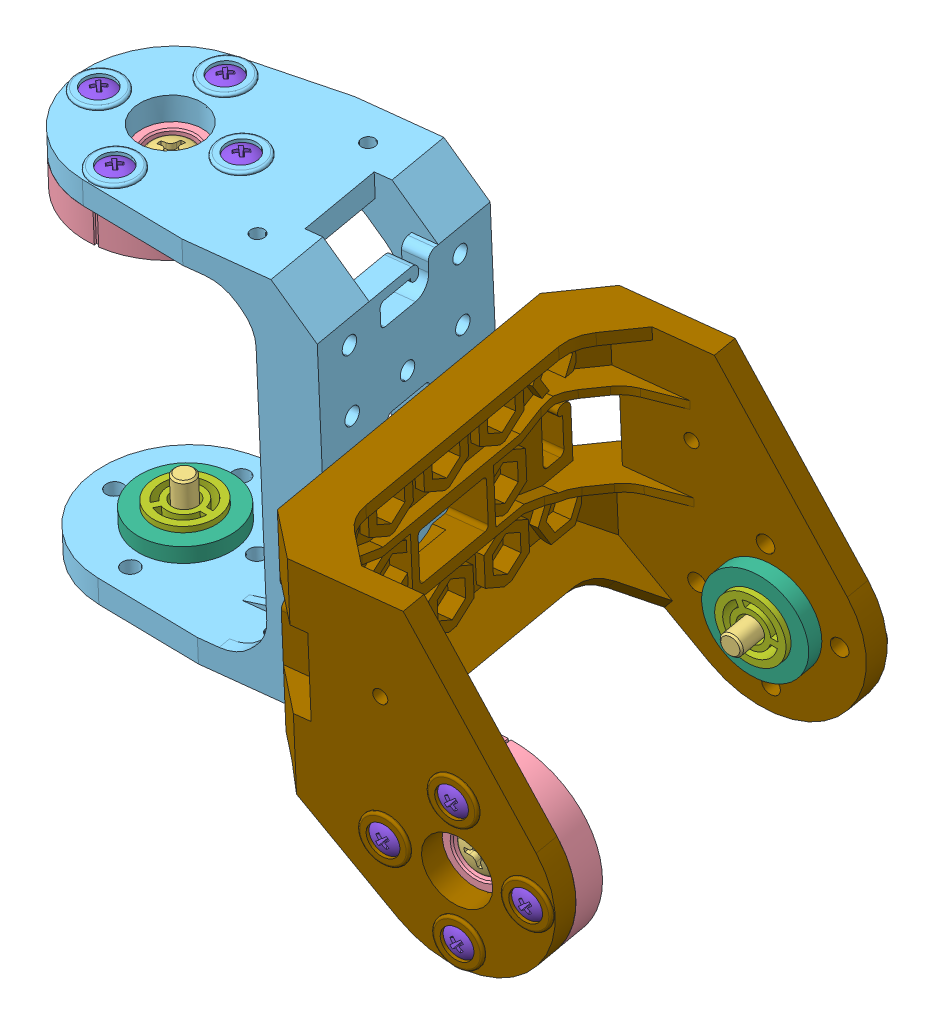
SolidWorks assembly bras, configuration Défaut. Lengths in mm.
Overall size (80.13 65.03 56.04).
31 component instances, 9 part files, 38 mates.
Components (placement in the parent):
- ASSY_GEAR-WHEEL___DUMMY-1: ASSY_GEAR-WHEEL___DUMMY [Défaut] at (-92.8438 48.768 19.6267) x (0.999774 -0.01458 -0.015465) z (0.015465 0.998153 0.058742) size (6.5 6.5 5.51)
- BHS_M2_6X8-1: BHS_M2_6X8 [Défaut] at (-92.8427 48.8379 19.6308) x (0.999774 -0.01458 -0.015465) z (0.015465 0.998153 0.058742) size (5.92 5.92 9.6)
  - BHS_M2_6X8-1: BHS_M2_6X8 [Défaut] at origin size (2.15 2.15 8)
  - BHS_M2_6X8-1-1: BHS_M2_6X8-1 [Défaut] at origin size (5.92 5.92 9.6)
- DC04_B01_HORN2_DUMMY-1: DC04_B01_HORN2_DUMMY [Défaut] at (-92.8427 48.8379 19.6308) x (-0.992163 0.008034 0.124691) z (0.015465 0.998153 0.058742) size (22 22 6.71)
- F2-1: F2 [Défaut] at (-92.8447 48.7081 19.6232) x (0.015465 0.998153 0.058742) z (0.992163 -0.008034 -0.124691) size (48.8 25 37)
- WA-1: WA [Défaut] at (-93.1695 27.7469 18.3896) x (0.999774 -0.01458 -0.015465) z (0.01458 -0.058968 0.998153) size (12 1.9 12)
- BU-1: BU [Défaut] at (-93.1293 30.3421 18.5423) x (0.999774 -0.01458 -0.015465) z (-0.01458 0.058968 -0.998153) size (10 7.1 10)
- BU-2: BU [Défaut] at (-46.8581 26.9638 -6.0328) x (0.982813 -0.130125 -0.130942) z (0.136768 0.989668 0.043041) size (10 7.1 10)
- WA-4: WA [Défaut] at (-47.1805 27.1204 -8.6079) x (0.982813 -0.130125 -0.130942) z (-0.136768 -0.989668 -0.043041) size (12 1.9 12)
- BHS_M2_6X8-2: BHS_M2_6X8 [Défaut] at (-45.0751 26.098 8.21) x (0.519447 -0.846526 -0.116487) z (-0.123989 0.06021 -0.990455) size (5.92 5.92 9.6)
  - BHS_M2_6X8-1: BHS_M2_6X8 [Défaut] at origin size (2.15 2.15 8)
  - BHS_M2_6X8-1-1: BHS_M2_6X8-1 [Défaut] at origin size (5.92 5.92 9.6)
- BHS_M2_6X8-3: BHS_M2_6X8 [Défaut] at (-92.9069 44.6955 19.387) x (-0.917934 -0.00912 0.396627) z (-0.015465 -0.998153 -0.058742) size (5.92 5.92 9.6)
  - BHS_M2_6X8-1: BHS_M2_6X8 [Défaut] at origin size (2.15 2.15 8)
  - BHS_M2_6X8-1-1: BHS_M2_6X8-1 [Défaut] at origin size (5.92 5.92 9.6)
- vis M2-12: vis M2 [B18.6.7M - M2 x 0.4 x 2.5 Type I Cross Recessed PHMS --2.5N] at (-93.4562 73.7443 13.1446) x (-0.015465 -0.998153 -0.058742) z (0.664013 0.033671 -0.746963) size (4.08 4 4)
- vis M2-13: vis M2 [B18.6.7M - M2 x 0.4 x 2.5 Type I Cross Recessed PHMS --2.5N] at (-100.4016 73.3269 22.0658) x (-0.015465 -0.998153 -0.058742) z (0.664013 0.033671 -0.746963) size (4.08 4 4)
- vis M2-14: vis M2 [B18.6.7M - M2 x 0.4 x 2.5 Type I Cross Recessed PHMS --2.5N] at (-84.527 73.1984 20.0707) x (-0.015465 -0.998153 -0.058742) z (0.664013 0.033671 -0.746963) size (4.08 4 4)
- vis M2-15: vis M2 [B18.6.7M - M2 x 0.4 x 2.5 Type I Cross Recessed PHMS --2.5N] at (-91.4724 72.781 28.9919) x (-0.015465 -0.998153 -0.058742) z (0.664013 0.033671 -0.746963) size (4.08 4 4)
- axe roue avec F1-1: axe roue avec F1 [Défaut] at (-44.2439 25.4602 13.5431) x (-0.984524 -0.132048 0.115219) z (0.123989 -0.06021 0.990455) size (38.99 42.39 48.8)
  - ASSY_GEAR-WHEEL___DUMMY-1: ASSY_GEAR-WHEEL___DUMMY [Défaut] at (0.1197 -0.3305 -1.3436) size (6.5 6.5 5.51)
  - BHS_M2_6X8-1: BHS_M2_6X8 [Défaut] at (0.1197 -0.3305 -1.2736) size (5.92 5.92 9.6)
    - BHS_M2_6X8-1: BHS_M2_6X8 [Défaut] at origin size (2.15 2.15 8)
    - BHS_M2_6X8-1-1: BHS_M2_6X8-1 [Défaut] at origin size (5.92 5.92 9.6)
  - DC04_B01_HORN2_DUMMY-1: DC04_B01_HORN2_DUMMY [Défaut] at (0.1197 -0.3305 -1.2736) x (0.990114 -0.140262 0) z (0 0 1) size (22 22 6.71)
  - F1-1: F1 [Défaut] at (0.1197 -0.3305 -1.4036) x (0 0 1) z (0.990114 -0.140262 0) size (48.8 38 34)
- vis M2-16: vis M2 [B18.6.7M - M2 x 0.4 x 2.5 Type I Cross Recessed PHMS --2.5N] at (-41.4029 32.36 37.0268) x (-0.123989 0.06021 -0.990455) z (0.755987 0.652273 -0.054985) size (4.08 4 4)
- vis M2-17: vis M2 [B18.6.7M - M2 x 0.4 x 2.5 Type I Cross Recessed PHMS --2.5N] at (-49.4639 24.4391 37.5543) x (-0.123989 0.06021 -0.990455) z (0.755987 0.652273 -0.054985) size (4.08 4 4)
- vis M2-18: vis M2 [B18.6.7M - M2 x 0.4 x 2.5 Type I Cross Recessed PHMS --2.5N] at (-33.5893 24.3105 35.5593) x (-0.123989 0.06021 -0.990455) z (0.755987 0.652273 -0.054985) size (4.08 4 4)
- vis M2-19: vis M2 [B18.6.7M - M2 x 0.4 x 2.5 Type I Cross Recessed PHMS --2.5N] at (-41.6503 16.3896 36.0869) x (-0.123989 0.06021 -0.990455) z (0.755987 0.652273 -0.054985) size (4.08 4 4)
Mates (geometry in assembly coordinates):
- Coaxiale2: concentric anti-aligned: cylinder of ASSY_GEAR-WHEEL___DUMMY-1 through (-92.6288 62.6423 20.4432) axis (0.015465 0.998153 0.058742) radius 2.9; cylinder of DC04_B01_HORN2_DUMMY-1 through (-92.567 66.6349 20.6782) axis (-0.015465 -0.998153 -0.058742) radius 2.95
- Coïncidente2: coincident anti-aligned: plane of ASSY_GEAR-WHEEL___DUMMY-1 through (-95.1288 66.5196 23.3131) normal (0.015465 0.998153 0.058742); plane of DC04_B01_HORN2_DUMMY-1 through (-89.1426 66.4256 23.3343) normal (-0.015465 -0.998153 -0.058742)
- Coaxiale3: concentric aligned: cylinder of BHS_M2_6X8-1/BHS_M2_6X8-1-1 through (-92.5415 68.2819 20.7751) axis (-0.015465 -0.998153 -0.058742) radius 1.3; cylinder of DC04_B01_HORN2_DUMMY-1 through (-92.5415 68.2819 20.7751) axis (-0.015465 -0.998153 -0.058742) radius 1.3
- Coïncidente3: coincident anti-aligned: plane of BHS_M2_6X8-1/BHS_M2_6X8-1-1 through (-95.0502 68.4638 18.3447) normal (-0.015465 -0.998153 -0.058742); plane of DC04_B01_HORN2_DUMMY-1 through (-89.1923 68.0853 23.233) normal (0.015465 0.998153 0.058742)
- Coïncidente4: coincident anti-aligned: plane of DC04_B01_HORN2_DUMMY-1 through (-79.7488 68.8888 30.7579) normal (0.015465 0.998153 0.058742); plane of F2-1 through (-70.6953 68.7229 31.1924) normal (-0.015465 -0.998153 -0.058742)
- Coaxiale4: concentric anti-aligned: cylinder of DC04_B01_HORN2_DUMMY-1 through (-84.6111 67.7684 19.7511) axis (0.015465 0.998153 0.058742) radius 1.05; cylinder of F2-1 through (-84.5517 71.6014 19.9767) axis (-0.015465 -0.998153 -0.058742) radius 1.05
- Coaxiale5: concentric anti-aligned: cone of DC04_B01_HORN2_DUMMY-1 through (-92.5231 69.4697 20.845) axis (-0.015465 -0.998153 -0.058742); cylinder of F2-1 through (-92.52 69.6693 20.8568) axis (0.015465 0.998153 0.058742) radius 4
- Coaxiale8: concentric anti-aligned: cylinder of F2-1 through (-93.2159 24.7524 18.2134) axis (0.015465 0.998153 0.058742) radius 4; cylinder of BU-1 through (-93.1293 30.3421 18.5423) axis (-0.015465 -0.998153 -0.058742) radius 4
- Coïncidente6: coincident anti-aligned: plane of F2-1 through (-70.1336 23.7958 28.391) normal (-0.015465 -0.998153 -0.058742); plane of BU-1 through (-93.2159 24.7524 18.2134) normal (0.015465 0.998153 0.058742)
- Coaxiale9: concentric anti-aligned: cylinder of WA-1 through (-93.1695 27.7469 18.3896) axis (0.015465 0.998153 0.058742) radius 4.025; cylinder of BU-1 through (-93.1293 30.3421 18.5423) axis (-0.015465 -0.998153 -0.058742) radius 4
- Coïncidente7: coincident anti-aligned: plane of F2-1 through (-71.3448 26.8005 28.7252) normal (0.015465 0.998153 0.058742); plane of WA-1 through (-87.1709 27.6594 18.2968) normal (-0.015465 -0.998153 -0.058742)
- Coaxiale12: concentric anti-aligned: cylinder of BU-2 through (-46.8581 26.9638 -6.0328) axis (-0.123989 0.06021 -0.990455) radius 4; cylinder of WA-4 through (-47.1805 27.1204 -8.6079) axis (0.123989 -0.06021 0.990455) radius 4.025
- Coaxiale14: concentric anti-aligned: cylinder of BU-2 through (-47.7384 27.3913 -13.065) axis (-0.123989 0.06021 -0.990455) radius 2.9; cylinder of BHS_M2_6X8-2/BHS_M2_6X8-1-1 through (-47.4904 27.2709 -11.0841) axis (0.123989 -0.06021 0.990455) radius 1.3
- Coïncidente11: coincident anti-aligned: plane of BU-2 through (-45.9179 27.0627 -11.2936) normal (-0.123989 0.06021 -0.990455); plane of BHS_M2_6X8-2/BHS_M2_6X8-1-1 through (-50.8662 28.0564 -10.6137) normal (0.123989 -0.06021 0.990455)
- Coaxiale15: concentric anti-aligned: cylinder of BU-1 through (-93.2391 23.2552 18.1252) axis (-0.015465 -0.998153 -0.058742) radius 2.9; cylinder of BHS_M2_6X8-3/BHS_M2_6X8-1-1 through (-93.2082 25.2515 18.2427) axis (0.015465 0.998153 0.058742) radius 1.3
- Coïncidente12: coincident anti-aligned: plane of BU-1 through (-91.6085 25.2282 18.218) normal (-0.015465 -0.998153 -0.058742); plane of BHS_M2_6X8-3/BHS_M2_6X8-1-1 through (-91.9184 25.4226 14.9961) normal (0.015465 0.998153 0.058742)
- Coaxiale26: concentric anti-aligned: cylinder of F2-1 through (-93.481 72.1473 13.0506) axis (-0.015465 -0.998153 -0.058742) radius 1.05; cylinder of vis M2-12 through (-93.0634 99.0974 14.6366) axis (0.015465 0.998153 0.058742) radius 1
- Coïncidente22: coincident anti-aligned: plane of F2-1 through (-103.9809 72.3683 12.0603) normal (0.015465 0.998153 0.058742); plane of vis M2-12 through (-94.2285 72.1979 12.3883) normal (-0.015465 -0.998153 -0.058742)
- Coaxiale27: concentric anti-aligned: cylinder of F2-1 through (-100.4263 71.7299 21.9718) axis (-0.015465 -0.998153 -0.058742) radius 1.05; cylinder of vis M2-13 through (-100.0088 98.68 23.5578) axis (0.015465 0.998153 0.058742) radius 1
- Coïncidente23: coincident anti-aligned: plane of F2-1 through (-103.9809 72.3683 12.0603) normal (0.015465 0.998153 0.058742); plane of vis M2-13 through (-101.1739 71.7805 21.3095) normal (-0.015465 -0.998153 -0.058742)
- Coaxiale28: concentric anti-aligned: cylinder of F2-1 through (-84.5517 71.6014 19.9767) axis (-0.015465 -0.998153 -0.058742) radius 1.05; cylinder of vis M2-14 through (-84.1342 98.5515 21.5628) axis (0.015465 0.998153 0.058742) radius 1
- Coïncidente24: coincident anti-aligned: plane of F2-1 through (-103.9809 72.3683 12.0603) normal (0.015465 0.998153 0.058742); plane of vis M2-14 through (-85.2993 71.6519 19.3144) normal (-0.015465 -0.998153 -0.058742)
- Coaxiale29: concentric anti-aligned: cylinder of F2-1 through (-91.4971 71.1839 28.8979) axis (-0.015465 -0.998153 -0.058742) radius 1.05; cylinder of vis M2-15 through (-91.0796 98.1341 30.4839) axis (0.015465 0.998153 0.058742) radius 1
- Coïncidente25: coincident anti-aligned: plane of F2-1 through (-103.9809 72.3683 12.0603) normal (0.015465 0.998153 0.058742); plane of vis M2-15 through (-92.2447 71.2345 28.2356) normal (-0.015465 -0.998153 -0.058742)
- Coïncidente26: coincident anti-aligned: plane of F2-1 through (-65.7422 27.993 28.0964) normal (0.992163 -0.008034 -0.124691); plane of axe roue avec F1-1/F1-1 through (-69.4212 54.6797 -2.8965) normal (-0.992163 0.008034 0.124691)
- Coaxiale31: concentric anti-aligned: cylinder of F2-1 through (-68.0409 48.0336 24.5542) axis (0.992163 -0.008034 -0.124691) radius 1.05; cylinder of axe roue avec F1-1/F1-1 through (-64.0723 48.0015 24.0555) axis (-0.992163 0.008034 0.124691) radius 1.05
- Coaxiale32: concentric anti-aligned: cylinder of F2-1 through (-70.0247 48.997 8.707) axis (0.992163 -0.008034 -0.124691) radius 1.05; cylinder of axe roue avec F1-1/F1-1 through (-66.0561 48.9648 8.2082) axis (-0.992163 0.008034 0.124691) radius 1.05
- Coïncidente27: coincident anti-aligned: plane of BU-2 through (-47.5524 27.301 -11.5793) normal (0.123989 -0.06021 0.990455); plane of axe roue avec F1-1/F1-1 through (-65.5577 55.159 -7.6318) normal (-0.123989 0.06021 -0.990455)
- Coïncidente28: coincident anti-aligned: plane of WA-4 through (-41.2836 26.3396 -9.3936) normal (-0.123989 0.06021 -0.990455); plane of axe roue avec F1-1/F1-1 through (-63.9282 54.9682 -4.8185) normal (0.123989 -0.06021 0.990455)
- Coaxiale35: concentric anti-aligned: cylinder of BU-2 through (-46.8581 26.9638 -6.0328) axis (-0.123989 0.06021 -0.990455) radius 4; cylinder of axe roue avec F1-1/F1-1 through (-47.5524 27.301 -11.5793) axis (0.123989 -0.06021 0.990455) radius 4
- Coaxiale36: concentric anti-aligned: cylinder of axe roue avec F1-1/F1-1 through (-41.6013 32.4564 35.442) axis (-0.123989 0.06021 -0.990455) radius 1.05; cylinder of vis M2-16 through (-38.2536 30.8307 62.1843) axis (0.123989 -0.06021 0.990455) radius 1
- Coïncidente29: coincident anti-aligned: plane of axe roue avec F1-1/F1-1 through (-51.7811 34.8308 36.8607) normal (0.123989 -0.06021 0.990455); plane of vis M2-16 through (-42.244 33.212 35.5684) normal (-0.123989 0.06021 -0.990455)
- Coaxiale37: concentric anti-aligned: cylinder of axe roue avec F1-1/F1-1 through (-49.6623 24.5354 35.9696) axis (-0.123989 0.06021 -0.990455) radius 1.05; cylinder of vis M2-17 through (-46.3146 22.9097 62.7119) axis (0.123989 -0.06021 0.990455) radius 1
- Coïncidente30: coincident anti-aligned: plane of axe roue avec F1-1/F1-1 through (-51.7811 34.8308 36.8607) normal (0.123989 -0.06021 0.990455); plane of vis M2-17 through (-50.305 25.291 36.096) normal (-0.123989 0.06021 -0.990455)
- Coaxiale38: concentric anti-aligned: cylinder of axe roue avec F1-1/F1-1 through (-33.7877 24.4069 33.9746) axis (-0.123989 0.06021 -0.990455) radius 1.05; cylinder of vis M2-18 through (-30.44 22.7812 60.7169) axis (0.123989 -0.06021 0.990455) radius 1
- Coïncidente31: coincident anti-aligned: plane of axe roue avec F1-1/F1-1 through (-51.7811 34.8308 36.8607) normal (0.123989 -0.06021 0.990455); plane of vis M2-18 through (-34.4304 25.1625 34.101) normal (-0.123989 0.06021 -0.990455)
- Coaxiale39: concentric anti-aligned: cylinder of axe roue avec F1-1/F1-1 through (-41.8487 16.4859 34.5022) axis (-0.123989 0.06021 -0.990455) radius 1.05; cylinder of vis M2-19 through (-38.501 14.8602 61.2444) axis (0.123989 -0.06021 0.990455) radius 1
- Coïncidente32: coincident anti-aligned: plane of axe roue avec F1-1/F1-1 through (-51.7811 34.8308 36.8607) normal (0.123989 -0.06021 0.990455); plane of vis M2-19 through (-42.4914 17.2415 34.6286) normal (-0.123989 0.06021 -0.990455)
